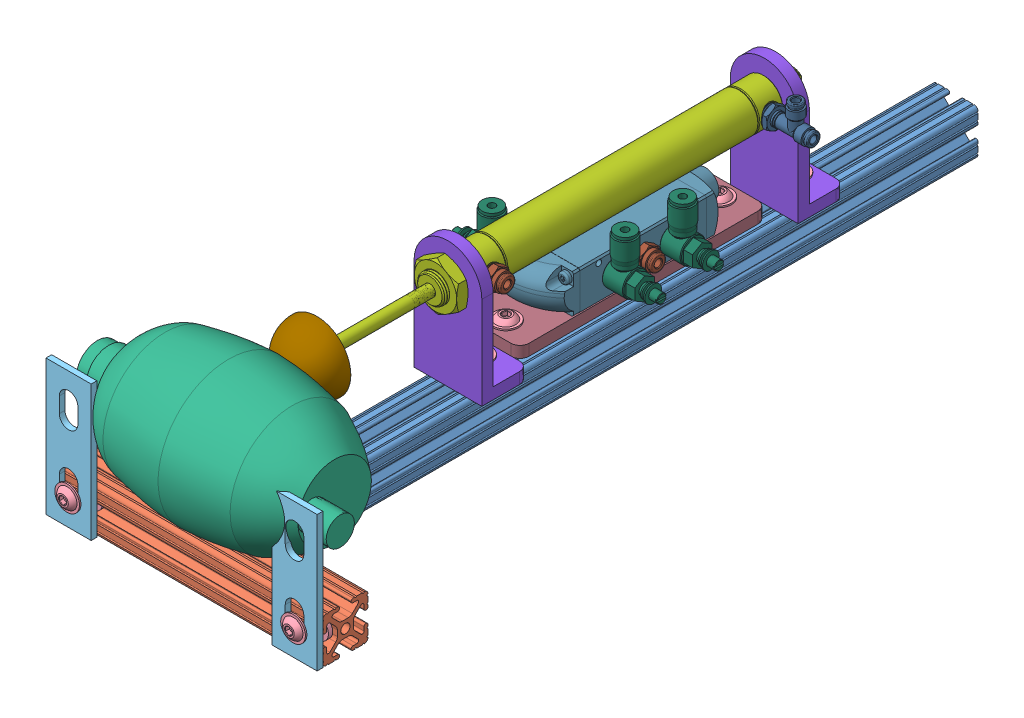
SolidWorks assembly FullAssembly, configuration Default. Lengths in mm.
Overall size (154.31 103.19 450.85).
40 component instances, 15 part files, 5 mates.
Components (placement in the parent):
- FrameSubAssembly-1: FrameSubAssembly [Default] at (-66.7757 29.2117 25.2907) size (154.3 103.19 450.85)
  - 47065T435_ALUMINUM T-SLOTTED FRAMING EXTRUSION cylinder piece-1: 47065T435_ALUMINUM T-SLOTTED FRAMING EXTRUSION cylinder piece [47065T435] at (185.1645 185.311 414.0747) size (25.4 25.4 406.4)
  - 47065T435_ALUMINUM T-SLOTTED FRAMING EXTRUSION cylinder piece2-1: 47065T435_ALUMINUM T-SLOTTED FRAMING EXTRUSION cylinder piece2 [47065T435] at (413.7645 185.311 528.3747) x (0 0 -1) z (1 0 0) size (25.4 25.4 152.4)
  - BracketSubAssembly-1: BracketSubAssembly [Default] at (199.8275 170.0389 519.1358) x (1 0 0) z (0 1 0) size (33.74 33.74 22.23)
    - 47065T236_ALUMINUM T-SLOTTED FRAMING EXTRUSION-1: 47065T236_ALUMINUM T-SLOTTED FRAMING EXTRUSION [47065T236] at (-1.9629 3.4611 16.8596) size (25.4 25.4 22.23)
    - 47065T142_ALUMINUM T-SLOTTED FRAMING EXTRUSION-3: 47065T142_ALUMINUM T-SLOTTED FRAMING EXTRUSION [47065T142] at (2.8123 16.1611 16.8596) x (0 -1 0) z (0 0 1) size (25.4 16.7 13.87)
    - 47065T142_ALUMINUM T-SLOTTED FRAMING EXTRUSION-4: 47065T142_ALUMINUM T-SLOTTED FRAMING EXTRUSION [47065T142] at (10.7371 8.2363 16.8596) size (25.4 16.7 13.87)
  - BracketSubAssembly-2: BracketSubAssembly [Default] at (170.5016 203.7582 519.1358) x (-1 0 0) z (0 -1 0) size (33.74 33.74 22.23)
    - 47065T236_ALUMINUM T-SLOTTED FRAMING EXTRUSION-1: 47065T236_ALUMINUM T-SLOTTED FRAMING EXTRUSION [47065T236] at (-1.9629 3.4611 16.8596) size (25.4 25.4 22.23)
    - 47065T142_ALUMINUM T-SLOTTED FRAMING EXTRUSION-3: 47065T142_ALUMINUM T-SLOTTED FRAMING EXTRUSION [47065T142] at (2.8123 16.1611 16.8596) x (0 -1 0) z (0 0 1) size (25.4 16.7 13.87)
    - 47065T142_ALUMINUM T-SLOTTED FRAMING EXTRUSION-4: 47065T142_ALUMINUM T-SLOTTED FRAMING EXTRUSION [47065T142] at (10.7371 8.2363 16.8596) size (25.4 16.7 13.87)
  - BagBracketSubAssembly-1: BagBracketSubAssembly [Default] at (195.5559 169.3719 579.2774) x (0 0 -1) z (1 0 0) size (16.7 76.2 25.4)
    - 2312N340_FLAT-SURFACE MACHINE BRACKET-1: 2312N340_FLAT-SURFACE MACHINE BRACKET [2312N34] at (38.2027 41.3392 53.1086) x (0 1 0) z (0 0 1) size (76.2 3.17 25.4)
    - 47065T142_ALUMINUM T-SLOTTED FRAMING EXTRUSION-1: 47065T142_ALUMINUM T-SLOTTED FRAMING EXTRUSION [47065T142] at (35.0277 17.9839 53.1086) x (0 0 1) z (0 -1 0) size (25.4 16.7 13.87)
  - BagBracketSubAssembly-2: BagBracketSubAssembly [Default] at (68.5559 169.3719 579.2774) x (0 0 -1) z (1 0 0) size (16.7 76.2 25.4)
    - 2312N340_FLAT-SURFACE MACHINE BRACKET-1: 2312N340_FLAT-SURFACE MACHINE BRACKET [2312N34] at (38.2027 41.3392 53.1086) x (0 1 0) z (0 0 1) size (76.2 3.17 25.4)
    - 47065T142_ALUMINUM T-SLOTTED FRAMING EXTRUSION-1: 47065T142_ALUMINUM T-SLOTTED FRAMING EXTRUSION [47065T142] at (35.0277 17.9839 53.1086) x (0 0 1) z (0 -1 0) size (25.4 16.7 13.87)
  - Bag-2: Bag [Default] at (187.8568 236.111 520.3841) x (0 -1 0) z (1 0 0) size (79.38 79.38 149.22)
- CylinderSubAssembly-1: CylinderSubAssembly [Default] at (-162.2994 131.4207 459.9069) x (0 0 -1) z (1 0 0) size (299.58 77.89 53.79)
  - 6498K636_ROUND BODY AIR CYLINDER-1: 6498K636_ROUND BODY AIR CYLINDER [6498K636] at (125.5713 147.8721 280.6882) size (267.72 27.5 23.81)
  - CylinderMount-1: CylinderMount [Default] at (40.1003 147.8721 280.6882) x (0 0 -1) z (1 0 0) size (38.1 71.12 26.35)
  - CylinderMount-3: CylinderMount [Default] at (217.9003 147.8721 280.6882) x (0 0 -1) z (1 0 0) size (38.1 71.12 26.35)
  - BagCompressorAttatchment-1: BagCompressorAttatchment [Default] at (-41.8941 147.8721 280.6882) x (0 1 0) z (0 0 1) size (38.1 17.96 38.1)
  - 47065T142_ALUMINUM T-SLOTTED FRAMING EXTRUSION-1: 47065T142_ALUMINUM T-SLOTTED FRAMING EXTRUSION [47065T142] at (235.3628 102.1521 280.6882) size (25.4 16.7 13.87)
  - 47065T142_ALUMINUM T-SLOTTED FRAMING EXTRUSION-2: 47065T142_ALUMINUM T-SLOTTED FRAMING EXTRUSION [47065T142] at (57.5628 102.1521 280.6882) size (25.4 16.7 13.87)
  - 5779K201_PUSH-TO-CONNECT TUBE FITTING FOR AIR (1)-1: 5779K201_PUSH-TO-CONNECT TUBE FITTING FOR AIR (1) [5779K201] at (211.0423 147.8721 285.1055) x (1 0 0) z (0 0 -1) size (11 20.83 30.61)
  - 5225K711_PUSH-TO-CONNECT TUBE FITTING FOR AIR (1)-4: 5225K711_PUSH-TO-CONNECT TUBE FITTING FOR AIR (1) [5225K711] at (54.5783 147.8721 284.5975) x (-1 0 0) z (0 0 -1) size (11 12.7 15.49)
  - 95462A505_GRADE 5 STEEL HEX NUT-1: 95462A505_GRADE 5 STEEL HEX NUT [95462A505] at (-47.4503 147.8721 280.6882) x (0 0 -1) z (1 0 0) size (11.11 12.83 7.01)
  - 95462A505_GRADE 5 STEEL HEX NUT-2: 95462A505_GRADE 5 STEEL HEX NUT [95462A505] at (-36.3378 147.8721 280.6882) x (0 0 -1) z (1 0 0) size (11.11 12.83 7.01)
- ControlSubAssembly-1: ControlSubAssembly [Default] at (-3.843 176.6888 382.3124) x (0 0 -1) z (1 0 0) size (145.26 49.82 88.3)
  - DirectionalValveMountingPlate-1: DirectionalValveMountingPlate [Default] at (64.2328 50.534 99.7528) size (138.91 6.35 34.92)
  - 6124K404_AIR DIRECTIONAL CONTROL VALVE-1: 6124K404_AIR DIRECTIONAL CONTROL VALVE [Default] at (64.2688 67.884 112.7528) x (0 1 0) z (-1 0 0) size (22.43 40.41 109.13)
  - 5225K711_PUSH-TO-CONNECT TUBE FITTING FOR AIR (1)-1: 5225K711_PUSH-TO-CONNECT TUBE FITTING FOR AIR (1) [5225K711] at (64.2688 67.884 123.5498) x (-1 0 0) z (0 0 -1) size (11 12.7 15.49)
  - 45045K36_AIR FLOW CONTROL VALVE-1: 45045K36_AIR FLOW CONTROL VALVE [Default] at (48.0688 67.8841 136.2528) x (0 1 0) z (1 0 0) size (30.5 35.17 14.2)
  - 45045K36_AIR FLOW CONTROL VALVE-2: 45045K36_AIR FLOW CONTROL VALVE [Default] at (80.4688 67.8839 136.2528) x (0 1 0) z (1 0 0) size (30.5 35.17 14.2)
  - 5225K711_PUSH-TO-CONNECT TUBE FITTING FOR AIR (1)-2: 5225K711_PUSH-TO-CONNECT TUBE FITTING FOR AIR (1) [5225K711] at (72.3688 67.884 101.9559) size (11 12.7 15.49)
  - 5225K711_PUSH-TO-CONNECT TUBE FITTING FOR AIR (1)-3: 5225K711_PUSH-TO-CONNECT TUBE FITTING FOR AIR (1) [5225K711] at (56.1688 67.884 101.9559) size (11 12.7 15.49)
  - 45045K36_AIR FLOW CONTROL VALVE-4: 45045K36_AIR FLOW CONTROL VALVE [Default] at (20.0688 70.184 89.3528) x (0 1 0) z (-1 0 0) size (30.5 35.17 14.2)
  - 47065T142_ALUMINUM T-SLOTTED FRAMING EXTRUSION-1: 47065T142_ALUMINUM T-SLOTTED FRAMING EXTRUSION [47065T142] at (4.5732 56.884 112.7068) size (25.4 16.7 13.87)
  - 47065T142_ALUMINUM T-SLOTTED FRAMING EXTRUSION-2: 47065T142_ALUMINUM T-SLOTTED FRAMING EXTRUSION [47065T142] at (124.4308 56.884 112.7068) size (25.4 16.7 13.87)
Mates (geometry in assembly coordinates):
- Coincident1: coincident anti-aligned: plane of FrameSubAssembly-1/47065T435_ALUMINUM T-SLOTTED FRAMING EXTRUSION cylinder piece-1 through (112.0557 227.2228 744.1654) normal (0 1 0); plane of CylinderSubAssembly-1/CylinderMount-3 through (118.3889 227.2228 242.0066) normal (0 -1 0)
- Distance1: distance = 6.35 mm aligned: plane of CylinderSubAssembly-1/CylinderMount-3 through (137.4389 279.2928 235.6566) normal (1 0 0); plane of FrameSubAssembly-1/47065T435_ALUMINUM T-SLOTTED FRAMING EXTRUSION cylinder piece-1 through (131.0889 220.8558 744.1654) normal (1 0 0)
- Distance2: distance = 4.7625 mm aligned: plane of ControlSubAssembly-1/DirectionalValveMountingPlate-1 through (126.3264 233.5728 387.2643) normal (1 0 0); plane of FrameSubAssembly-1/47065T435_ALUMINUM T-SLOTTED FRAMING EXTRUSION cylinder piece-1 through (131.0889 220.8558 744.1654) normal (1 0 0)
- Coincident6: coincident anti-aligned: plane of FrameSubAssembly-1/47065T435_ALUMINUM T-SLOTTED FRAMING EXTRUSION cylinder piece-1 through (127.9393 227.2228 744.1654) normal (0 1 0); plane of ControlSubAssembly-1/DirectionalValveMountingPlate-1 through (95.9099 227.2228 318.0796) normal (0 -1 0)
- Distance3: distance = 6.35 mm anti-aligned: plane of ControlSubAssembly-1/DirectionalValveMountingPlate-1 through (126.3264 233.5728 248.3566) normal (0 0 -1); plane of CylinderSubAssembly-1/CylinderMount-3 through (118.3889 279.2928 242.0066) normal (0 0 1)
